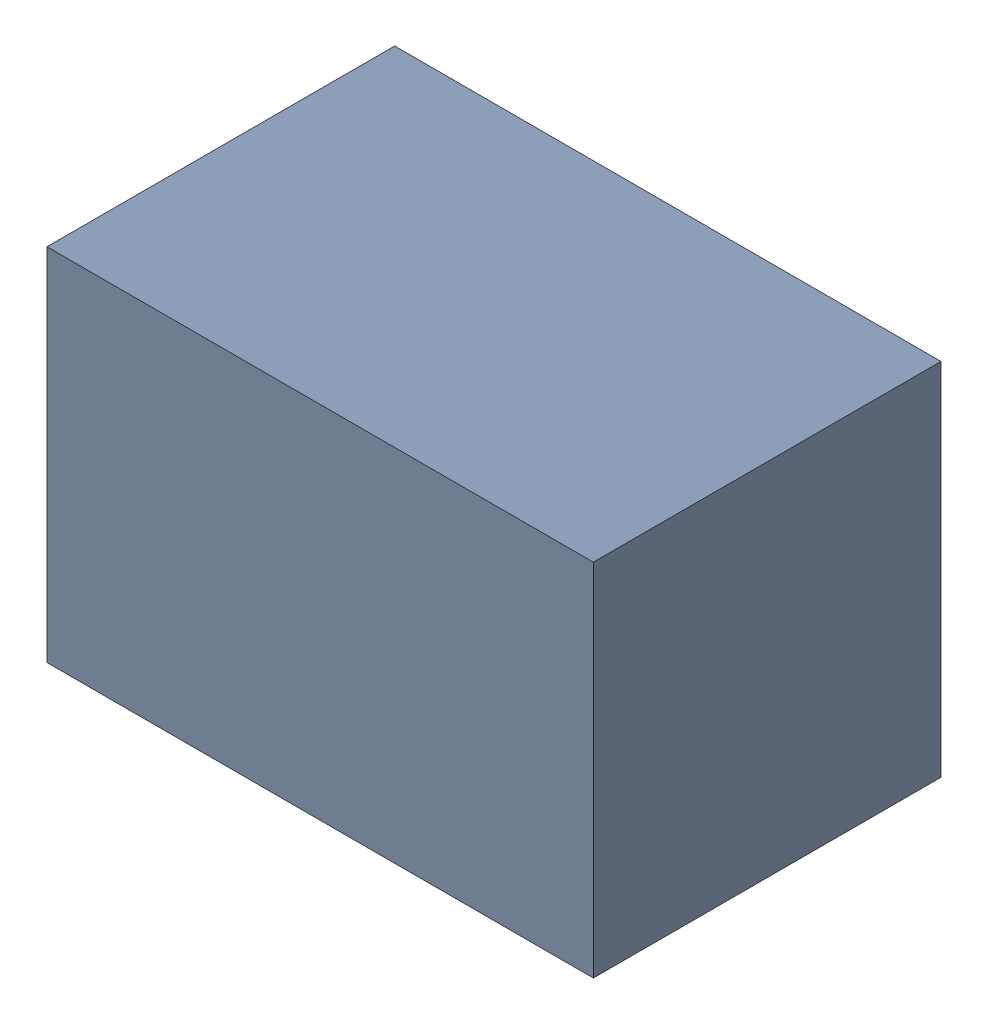
SolidWorks assembly C21, configuration Default. Lengths in mm.
Overall size (2.2 1.45 1.4).
2 component instances, 1 part files, 0 mates.
Components (placement in the parent):
- 1017092848-1: 1017092848 [Default] at (121.92 144.78 0) size (2.2 1.45 1.4)
  - Extruded_3-1: Extruded_3 [Default] at origin size (2.2 1.45 1.4)
